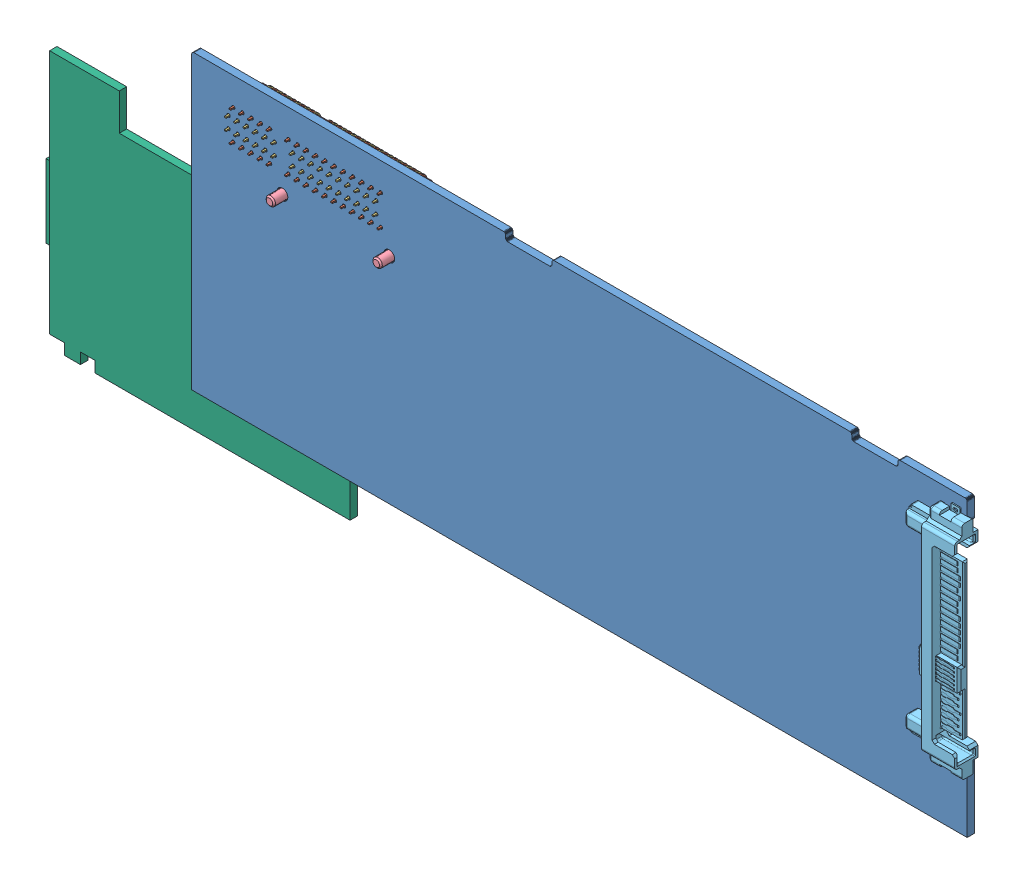
SolidWorks assembly K2v3, configuration Default. Lengths in mm.
Overall size (209.3 77.43 25.7).
9 component instances, 6 part files, 9 mates.
Components (placement in the parent):
- u2CEM.step-1: u2CEM.step [Default] at origin size (168 63.5 1.6)
  - u2CEM PCB.step-1: u2CEM PCB.step [Default] at origin size (168 63.5 1.6)
- PCIE-064-02-X-D-RA-1: PCIE-064-02-X-D-RA [Default] at (236.4945 -103.501 -5.8) x (-1 0 0) z (0 0 1) size (39 18.85 13.86)
  - PCIE-064-02-X-D-RA.step-1: PCIE-064-02-X-D-RA.step [Default] at origin size (39 18.85 13.86)
    - PCIE-064-02-F-D-RA_pins2.step-1: PCIE-064-02-F-D-RA_pins2.step [Default] at (6.9945 0 0) size (34 17.93 10.46)
    - PCIE-064-02-F-D-RA_pins1.step-1: PCIE-064-02-F-D-RA_pins1.step [Default] at (6.9945 0 0) size (34 16.93 10.47)
    - PCIE-064-02-F-D-RA_body.step-1: PCIE-064-02-F-D-RA_body.step [Default] at origin size (39 18.85 13.86)
- 3d_model_psas4m213002xxx-1: 3d_model_psas4m213002xxx [Default] at (374.1 -116.95 3.6) x (0 1 0) z (0 0 -1) size (49.45 12.58 5.15)
- CEM_NIC-1: CEM_NIC [Default] at (239.7 -107.1 -6.6) x (-1 0 0) z (0 0 1) size (67.47 60.32 15.1)
Mates (geometry in assembly coordinates):
- Parallel1: parallel aligned: plane of u2CEM.step-1/u2CEM PCB.step-1 through (212 -153.5 0) normal (-1 0 0); plane of PCIE-064-02-X-D-RA-1/PCIE-064-02-X-D-RA.step-1/PCIE-064-02-F-D-RA_body.step-1 through (217 -113.85 0) normal (-1 0 0)
- Coincident1: coincident anti-aligned: plane of u2CEM.step-1/u2CEM PCB.step-1 through (298.5644 -121.4016 0) normal (0 0 -1); plane of PCIE-064-02-X-D-RA-1/PCIE-064-02-X-D-RA.step-1/PCIE-064-02-F-D-RA_body.step-1 through (256 -113.85 0) normal (0 0 1)
- Concentric1: concentric anti-aligned: cylinder of u2CEM.step-1/u2CEM PCB.step-1 through (231.65 -107 -0.8) axis (0 0 1) radius 1.175; cylinder of PCIE-064-02-X-D-RA-1/PCIE-064-02-X-D-RA.step-1/PCIE-064-02-F-D-RA_body.step-1 through (231.65 -107 -0.2949) axis (0 0 -1) radius 1
- Concentric2: concentric anti-aligned: cylinder of u2CEM.step-1/u2CEM PCB.step-1 through (371.2 -97.48 -0.8) axis (0 0 1) radius 0.825; cylinder of 3d_model_psas4m213002xxx-1 through (371.2 -97.48 2.0115) axis (0 0 -1) radius 0.7
- Coincident2: coincident anti-aligned: plane of u2CEM.step-1/u2CEM PCB.step-1 through (298.5644 -121.4016 1.6) normal (0 0 1); plane of 3d_model_psas4m213002xxx-1 through (377.7 -92.95 1.6) normal (0 0 -1)
- Parallel2: parallel aligned: plane of u2CEM.step-1/u2CEM PCB.step-1 through (376 -100 0) normal (1 0 0); plane of 3d_model_psas4m213002xxx-1 through (376.4 -116.95 3.6) normal (1 0 0)
- Coincident3: coincident: plane of PCIE-064-02-X-D-RA-1/PCIE-064-02-X-D-RA.step-1/PCIE-064-02-F-D-RA_body.step-1 through (230.6 -114.5546 -6.7) normal (-1 0 0); plane of CEM_NIC-1 through (230.6 -107.1 -3.722) normal (1 0 0)
- Coincident4: coincident: plane of PCIE-064-02-X-D-RA-1/PCIE-064-02-X-D-RA.step-1/PCIE-064-02-F-D-RA_body.step-1 through (236.4945 -114.55 -5.8) normal (0 -1 0); line of CEM_NIC-1 through (232.5 -114.55 -3.722) axis (0 0 -1)
- Distance1: distance = 0.1 mm anti-aligned: plane of CEM_NIC-1 through (217.65 -118.05 -6.6) normal (0 0 -1); plane of PCIE-064-02-X-D-RA-1/PCIE-064-02-X-D-RA.step-1/PCIE-064-02-F-D-RA_body.step-1 through (218.95 -114.5546 -6.7) normal (0 0 1)
